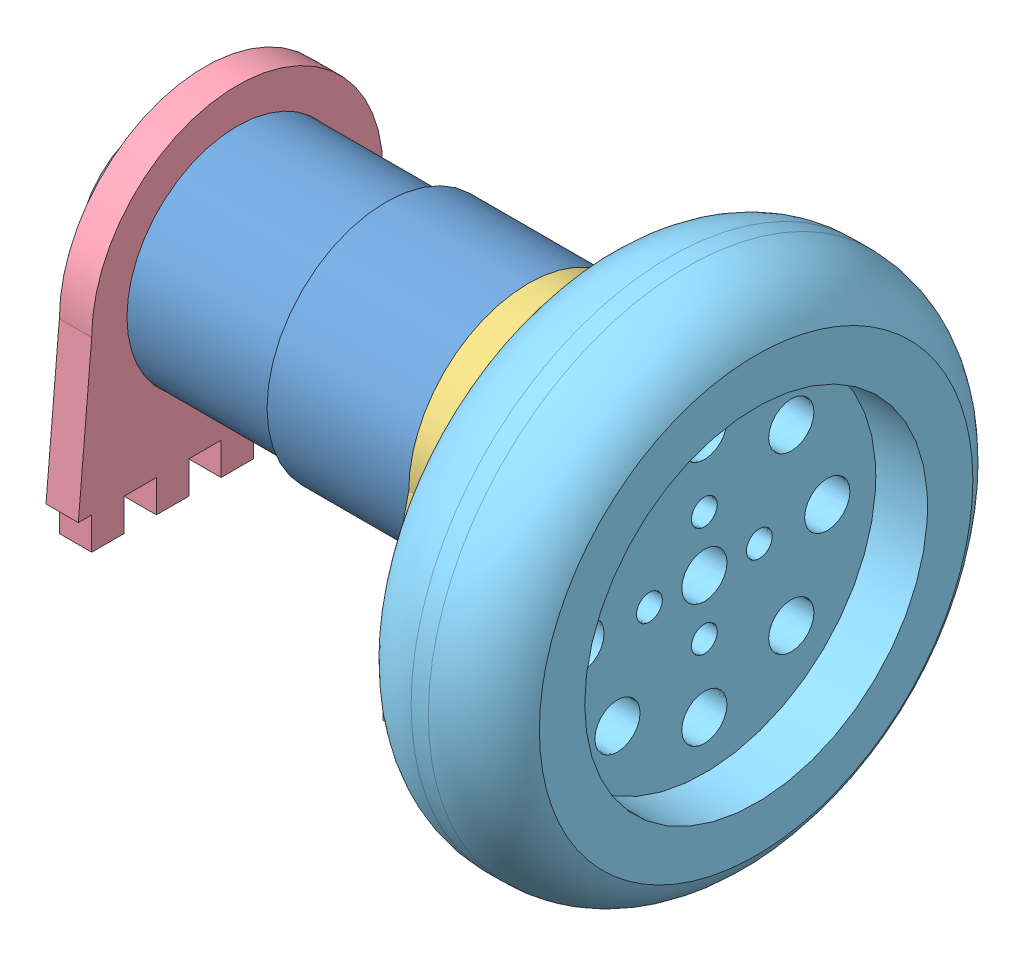
SolidWorks assembly ensemble tournant, configuration Défaut. Lengths in mm.
Overall size (92.8 80 80).
5 component instances, 5 part files, 10 mates.
Components (placement in the parent):
- Moteur roues-1: Moteur roues [Défaut] at (-11.3267 5.7717 79.6) size (79.6 36.8 36.8)
- Moyeu Roue Moteur-1: Moyeu Roue Moteur [Défaut] at (57.3734 -1.2283 79.6) x (1 0 0) z (0 -0.700442 -0.713709) size (12.7 22.1 22.1)
- support moteur avant-1: support moteur avant [Défaut] at (10.6733 5.7717 79.6) x (0 0 1) z (1 0 0) size (45 47.25 5)
- suppot moteur arriere-1: suppot moteur arriere [Défaut] at (-39.3267 5.7717 79.6) x (0 0 1) z (1 0 0) size (49.13 51.25 5)
- nouvelles-roues4-1: nouvelles-roues4 [Défaut] at (45.8733 -1.2283 79.6) x (0 0 1) z (-1 0 0) size (80 80 24)
Mates (geometry in assembly coordinates):
- Coaxiale1: concentric aligned: cylinder of Moteur roues-1 through (-2.916 -1.2283 79.6) axis (-1 0 0) radius 3; cylinder of Moyeu Roue Moteur-1 through (29.8733 -1.2283 79.6) axis (-1 0 0) radius 3
- Coïncidente2: coincident anti-aligned: plane of Moteur roues-1 through (17.1733 4.7717 79.6) normal (1 0 0); plane of Moyeu Roue Moteur-1 through (17.1733 -1.2283 79.6) normal (-1 0 0)
- Coaxiale3: concentric anti-aligned: cylinder of Moteur roues-1 through (-70.4446 5.7717 79.6) axis (-1 0 0) radius 17; circle of suppot moteur arriere-1
- Coïncidente6: coincident aligned: plane of support moteur avant-1 through (15.6733 -22.9783 79.6) normal (0 -1 0); plane of suppot moteur arriere-1 through (-34.3267 -22.9783 54.6) normal (0 -1 0)
- Coaxiale6: concentric anti-aligned: cylinder of Moteur roues-1 through (-2.916 -1.2283 79.6) axis (-1 0 0) radius 6; cylinder of support moteur avant-1 through (10.6733 -1.2283 79.6) axis (1 0 0) radius 6.25
- Coaxiale7: concentric aligned: cylinder of Moteur roues-1 through (5.6733 19.195 87.35) axis (1 0 0) radius 1.5; cylinder of support moteur avant-1 through (10.6733 19.195 87.35) axis (1 0 0) radius 1.5
- Coïncidente7: coincident anti-aligned: plane of Moteur roues-1 through (10.6733 24.1717 79.6) normal (1 0 0); plane of support moteur avant-1 through (10.6733 5.7717 79.6) normal (-1 0 0)
- Distance1: distance = 50 mm aligned: plane of support moteur avant-1 through (10.6733 5.7717 79.6) normal (-1 0 0); plane of suppot moteur arriere-1 through (-39.3267 5.7717 79.6) normal (-1 0 0)
- Coaxiale8: concentric anti-aligned: cylinder of Moteur roues-1 through (-2.916 -1.2283 79.6) axis (-1 0 0) radius 3; cylinder of nouvelles-roues4-1 through (76.8503 -1.2283 79.6) axis (1 0 0) radius 3.5
- Coïncidente8: coincident anti-aligned: plane of Moyeu Roue Moteur-1 through (29.8733 2.0637 82.9544) normal (1 0 0); plane of nouvelles-roues4-1 through (29.8733 -1.2283 79.6) normal (-1 0 0)
